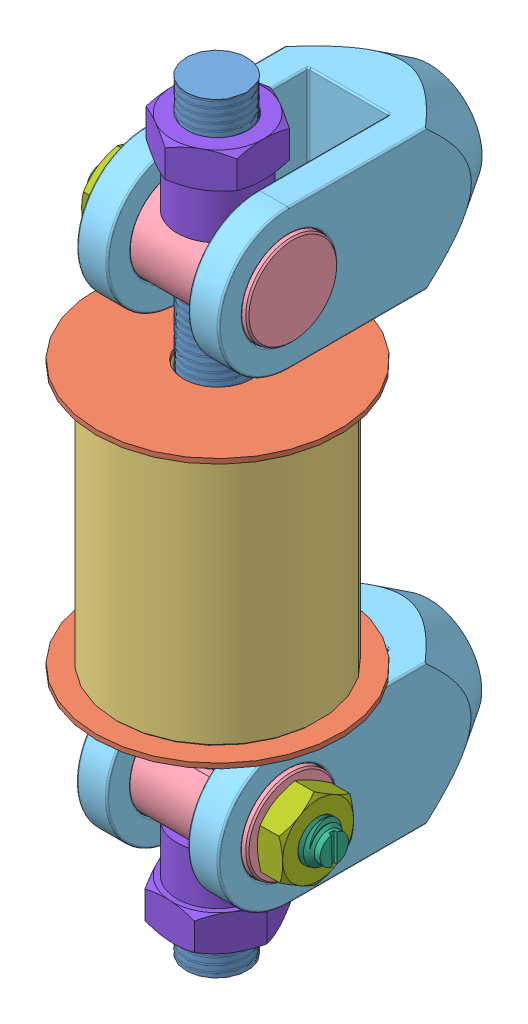
SolidWorks assembly Balance Bar Assembly, configuration Default. Lengths in mm.
Overall size (38.1 121.21 52.31).
14 component instances, 8 part files, 31 mates.
Components (placement in the parent):
- Balance bar-1: Balance bar [Default] at origin size (20.15 121.21 20.15)
- Washer-1: Washer [Default] at (0.1541 -20.32 0) x (0 -1 0) z (0 0 1) size (0.76 38.1 38.1)
- Washer-2: Washer [Default] at (0.1541 20.32 0) x (0 1 0) z (0 0 1) size (0.76 38.1 38.1)
- Bushing-1: Bushing [Default] at (0.1541 -20.32 0) x (0 1 0) z (0 0 1) size (40.64 31.75 31.75)
- clevis pin-1: clevis pin [Default] at (-11.6442 36.3537 0) x (0 0 1) z (0 1 0) size (14.27 23.6 14.27)
- clevis pin-2: clevis pin [Default] at (11.9524 -36.3537 0) x (0 0 1) z (0 -1 0) size (14.27 23.6 14.27)
- clevis-1: clevis [Default] at (-10.9584 36.3537 0) x (0 -1 0) z (0 0 1) size (21.97 22.28 44.25)
- clevis-2: clevis [Default] at (-11.0092 -36.3537 0) x (0 -1 0) z (0 0 1) size (21.97 22.28 44.25)
- 3408A532_Slotted Spring Plunger with 440C Stainless Steel Ball-Nose-1: 3408A532_Slotted Spring Plunger with 440C Stainless Steel Ball-Nose [3408A532] at (11.7175 -36.3537 0) x (0 0.999996 0.00283) z (0 -0.00283 0.999996) size (6.44 14.38 6.42)
- 3408A532_Slotted Spring Plunger with 440C Stainless Steel Ball-Nose-2: 3408A532_Slotted Spring Plunger with 440C Stainless Steel Ball-Nose [3408A532] at (-11.4092 36.3537 0) x (0 -0.999256 -0.038563) z (0 -0.038563 0.999256) size (6.44 14.38 6.42)
- 94846A505_Medium-Strength Steel Thin Hex Nut-1: 94846A505_Medium-Strength Steel Thin Hex Nut [94846A505] at (-13.6285 36.3537 0) x (0 0.825304 0.564688) z (0 -0.564688 0.825304) size (11.11 4.67 12.83)
- 94846A505_Medium-Strength Steel Thin Hex Nut-2: 94846A505_Medium-Strength Steel Thin Hex Nut [94846A505] at (13.9368 -36.3537 0) x (0 0.023573 -0.999722) z (0 0.999722 0.023573) size (11.11 4.67 12.83)
- 94846A515_Medium-Strength Steel Thin Hex Nut-1: 94846A515_Medium-Strength Steel Thin Hex Nut [94846A515] at (0.1541 51.8319 0) size (14.29 13.96 16.5)
- 94846A515_Medium-Strength Steel Thin Hex Nut-2: 94846A515_Medium-Strength Steel Thin Hex Nut [94846A515] at (0.1541 -51.8319 0) x (-0.837169 0 -0.546944) z (-0.546944 0 0.837169) size (14.29 13.96 16.5)
Mates (geometry in assembly coordinates):
- Coincident3: coordinate: point of Balance bar-1
- Concentric1: concentric anti-aligned: circle of Balance bar-1; circle of Washer-2
- Concentric2: concentric anti-aligned: circle of Balance bar-1; circle of Washer-1
- Concentric3: concentric anti-aligned: circle of Balance bar-1; circle of Bushing-1
- Concentric4: concentric anti-aligned: circle of Washer-2; circle of clevis pin-1
- Concentric5: concentric anti-aligned: circle of Washer-1; circle of clevis pin-2
- Concentric6: concentric anti-aligned: circle of clevis pin-1; circle of clevis-1
- Distance4: distance = 0.635 mm aligned: plane of clevis pin-1 through (11.9524 36.3537 0) normal (1 0 0); plane of clevis-1 through (11.3174 36.3537 0) normal (1 0 0)
- Concentric7: concentric anti-aligned: circle of clevis pin-2; circle of clevis-2
- Distance3: distance = 0.635 mm aligned: plane of clevis pin-2 through (-11.6442 -36.3537 0) normal (-1 0 0); plane of clevis-2 through (-11.0092 -36.3537 0) normal (-1 0 0)
- Concentric8: concentric anti-aligned: circle of clevis pin-1; circle of 3408A532_Slotted Spring Plunger with 440C Stainless Steel Ball-Nose-2
- Concentric9: concentric anti-aligned: circle of clevis pin-2; circle of 3408A532_Slotted Spring Plunger with 440C Stainless Steel Ball-Nose-1
- Concentric10: concentric aligned: circle of 3408A532_Slotted Spring Plunger with 440C Stainless Steel Ball-Nose-1; circle of 94846A505_Medium-Strength Steel Thin Hex Nut-2
- Concentric11: concentric anti-aligned: circle of 3408A532_Slotted Spring Plunger with 440C Stainless Steel Ball-Nose-2; circle of 94846A505_Medium-Strength Steel Thin Hex Nut-1
- Concentric12: concentric anti-aligned: circle of Washer-1; circle of 94846A515_Medium-Strength Steel Thin Hex Nut-2
- Concentric13: concentric aligned: cylinder of Bushing-1 through (0.1541 20.32 0) axis (0 -1 0) radius 12.7; circle of 94846A515_Medium-Strength Steel Thin Hex Nut-1
- Distance1: distance = 20.32 mm anti-aligned: plane of Bushing-1 through (0.1541 -20.32 0) normal (0 -1 0)
- Coincident10: coincident anti-aligned: plane of Washer-1 through (0.1541 -20.32 0) normal (0 1 0); plane of Bushing-1 through (0.1541 -20.32 0) normal (0 -1 0)
- Coincident11: coincident anti-aligned: plane of Washer-2 through (0.1541 20.32 0) normal (0 -1 0); plane of Bushing-1 through (0.1541 20.32 0) normal (0 1 0)
- Coincident12: coincident anti-aligned: plane of clevis pin-2 through (0.1541 -41.4337 0) normal (0 -1 0); plane of 94846A515_Medium-Strength Steel Thin Hex Nut-2 through (0.1541 -41.4337 0) normal (0 1 0)
- Coincident13: coincident anti-aligned: plane of clevis pin-1 through (0.1541 41.4337 0) normal (0 1 0); plane of 94846A515_Medium-Strength Steel Thin Hex Nut-1 through (0.1541 41.4337 0) normal (0 -1 0)
- Parallel1: parallel aligned: plane of Balance bar-1 through (0 59.69 0) normal (0 1 0); plane of clevis-1 through (11.3174 47.3392 0) normal (0 1 0)
- Parallel2: parallel aligned: plane of Balance bar-1 through (0 -59.69 0) normal (0 -1 0); plane of clevis-2 through (11.2666 -47.3392 0) normal (0 -1 0)
- Parallel6: parallel anti-aligned: plane of clevis-2 through (-11.0092 -36.3537 0) normal (-1 0 0)
- Parallel7: parallel anti-aligned: plane of clevis-1 through (-10.9584 36.3537 0) normal (-1 0 0)
- Distance5: distance = 5.08 mm aligned: plane of 94846A515_Medium-Strength Steel Thin Hex Nut-2 through (8.3905 -54.61 0.4544) normal (0 -1 0); plane of Balance bar-1 through (0 -59.69 0) normal (0 -1 0)
- Distance6: distance = 5.08 mm aligned: plane of 94846A515_Medium-Strength Steel Thin Hex Nut-1 through (-6.9896 54.61 -4.1244) normal (0 1 0); plane of Balance bar-1 through (0 59.69 0) normal (0 1 0)
- Coincident14: coincident anti-aligned: plane of clevis pin-2 through (11.9524 -36.3537 0) normal (1 0 0); plane of 94846A505_Medium-Strength Steel Thin Hex Nut-2 through (11.9524 -39.6917 5.4791) normal (-1 0 0)
- Coincident15: coincident anti-aligned: plane of clevis pin-1 through (-11.6442 36.3537 0) normal (-1 0 0); plane of 94846A505_Medium-Strength Steel Thin Hex Nut-1 through (-11.6442 33.5796 -5.785) normal (1 0 0)
- Distance7: distance = 2.54 mm aligned: plane of 3408A532_Slotted Spring Plunger with 440C Stainless Steel Ball-Nose-1 through (18.4612 -36.3537 0) normal (1 0 0); plane of 94846A505_Medium-Strength Steel Thin Hex Nut-2 through (15.9212 -39.6917 5.4791) normal (1 0 0)
- Distance8: distance = 2.54 mm aligned: plane of 3408A532_Slotted Spring Plunger with 440C Stainless Steel Ball-Nose-2 through (-18.1529 36.3537 0) normal (-1 0 0); plane of 94846A505_Medium-Strength Steel Thin Hex Nut-1 through (-15.6129 33.5796 -5.785) normal (-1 0 0)
